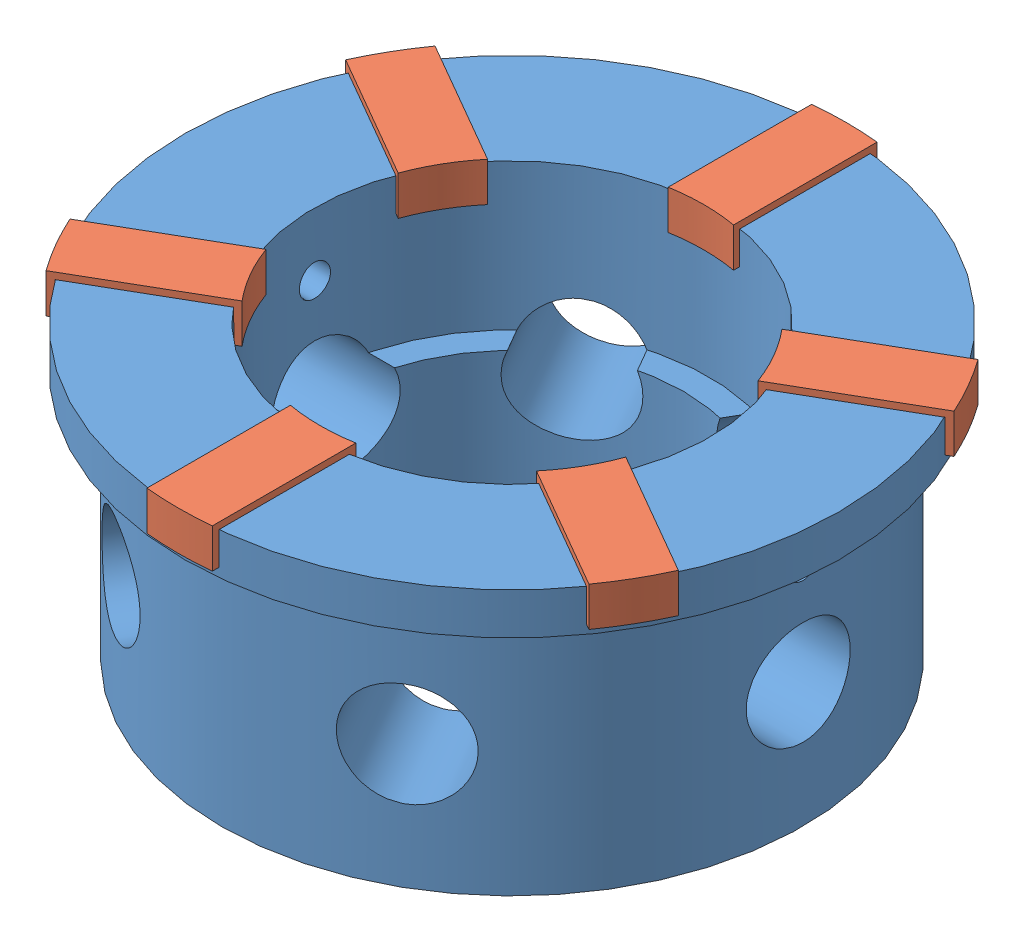
SolidWorks assembly FLANGE, configuration Default. Lengths in mm.
Overall size (100.08 45.45 102.08).
7 component instances, 2 part files, 5 mates.
Components (placement in the parent):
- 3 X 2 ABS BUSHING-1: 3 X 2 ABS BUSHING [1608T172] x (0 -1 0) z (0 0 1) size (44.45 100.08 100.08)
- VELCRO D-1: VELCRO D [Default] at (0 39.45 0) size (10 6 22.18)
- VELCRO D-2: VELCRO D [Default] at (0 39.45 0) x (0.5 0 0.866025) z (-0.866025 0 0.5) size (10 6 22.18)
- VELCRO D-3: VELCRO D [Default] at (0 39.45 0) x (-0.5 0 0.866025) z (-0.866025 0 -0.5) size (10 6 22.18)
- VELCRO D-4: VELCRO D [Default] at (0 39.45 0) x (-1 0 0) z (0 0 -1) size (10 6 22.18)
- VELCRO D-5: VELCRO D [Default] at (0 39.45 0) x (-0.5 0 -0.866025) z (0.866025 0 -0.5) size (10 6 22.18)
- VELCRO D-6: VELCRO D [Default] at (0 39.45 0) x (0.5 0 -0.866025) z (0.866025 0 0.5) size (10 6 22.18)
Mates (geometry in assembly coordinates):
- Coincident2: coincident anti-aligned: plane of 3 X 2 ABS BUSHING-1; plane of assembly through (0 0 0) normal (0 1 0)
- Coincident3: coincident aligned: plane of 3 X 2 ABS BUSHING-1; plane of assembly through (0 0 0) normal (1 0 0)
- Coincident4: coincident aligned: plane of 3 X 2 ABS BUSHING-1 through (0 0 0) normal (0 0 1); plane of assembly through (0 0 0) normal (0 0 1)
- Concentric1: concentric aligned: cone of 3 X 2 ABS BUSHING-1 through (0 22.225 0) axis (0 -1 0); cylinder of VELCRO D-1 through (0 44.45 0) axis (0 -1 0) radius 30.2895
- Coincident5: coincident anti-aligned: plane of 3 X 2 ABS BUSHING-1 through (-34.3535 44.45 0) normal (0 1 0); plane of VELCRO D-1 through (0 44.45 0) normal (0 -1 0)
